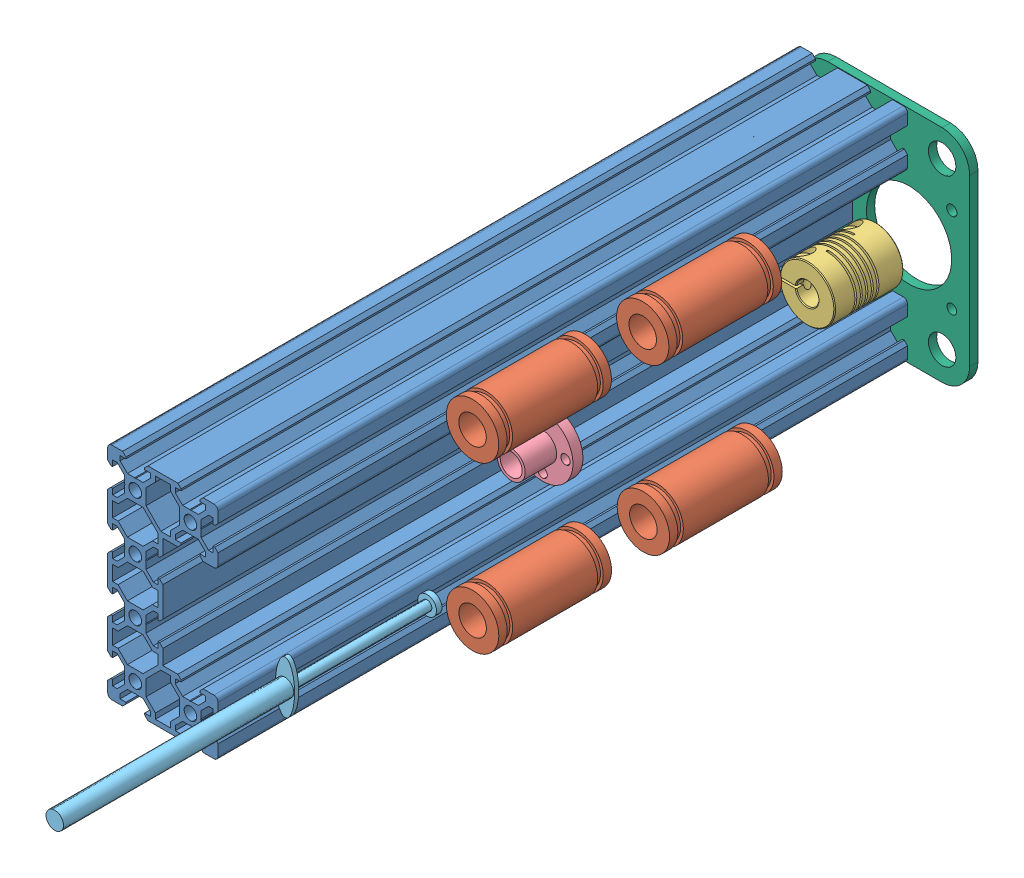
SolidWorks assembly pump_asembly, configuration Default. Lengths in mm.
Overall size (78.17 88.03 341.59).
13 component instances, 9 part files, 0 mates.
Components (placement in the parent):
- C-Beam 40x80x250 Linear Rail-2: C-Beam 40x80x250 Linear Rail [Default] at (125.6746 -111.8662 -206.616) size (40 80 250)
- Nema 17 Stepper Motor-2: Nema 17 Stepper Motor [Default] at (145.9607 -111.6142 -209.692) size (42.42 42.42 72) (hidden)
- bushing_10mm_id-1: bushing_10mm_id [Default] at (157.9728 -81.605 -54.5595) x (0 0 -1) z (1 0 0) size (40.86 19 19)
- bushing_10mm_id-2: bushing_10mm_id [Default] at (157.9739 -141.5707 -54.5889) x (0 0 -1) z (1 0 0) size (40.86 19 19)
- bushing_10mm_id-3: bushing_10mm_id [Default] at (158.1314 -81.5905 -116.0956) x (0 0 -1) z (1 0 0) size (40.86 19 19)
- bushing_10mm_id-4: bushing_10mm_id [Default] at (157.9338 -141.5647 -116.532) x (0 0 -1) z (1 0 0) size (40.86 19 19)
- Flexible Coupling 5mm x 8mm-1: Flexible Coupling 5mm x 8mm [Default] at (145.9021 -111.68 -194.9764) x (-1 0 0) z (0 0 -1) size (21.03 20 25)
- acme_nut_8mm-2: acme_nut_8mm [Default] at (145.8576 -111.6623 -77.7351) x (-1 0 0) z (0 1 0) size (22 15 22)
- syringe_1ml-1: syringe_1ml [Default] at (174.8658 -111.6498 46.7686) x (0 1 0) z (1 0 0) size (19.05 137 6.91)
- laser_cut_end_plates_3mm-1: laser_cut_end_plates_3mm [Default] at (0.0593 0.0097 -209.8168) size (61.43 80.03 3)
- laser_cut_front_plate_flat_3mm-1: laser_cut_front_plate_flat_3mm [Default] at (-0.1381 0.5477 46.507) size (58.85 80.03 3) (hidden)
- laser_cut_front_plate_holder_3mm-1: laser_cut_front_plate_holder_3mm [Default] at (-0.4013 0.2591 43.3259) size (73.95 80.03 3) (hidden)
- laser_cut_front_plate_holder_3mm-2: laser_cut_front_plate_holder_3mm [Default] at (-0.3436 0.4606 50.225) size (73.95 80.03 3) (hidden)
